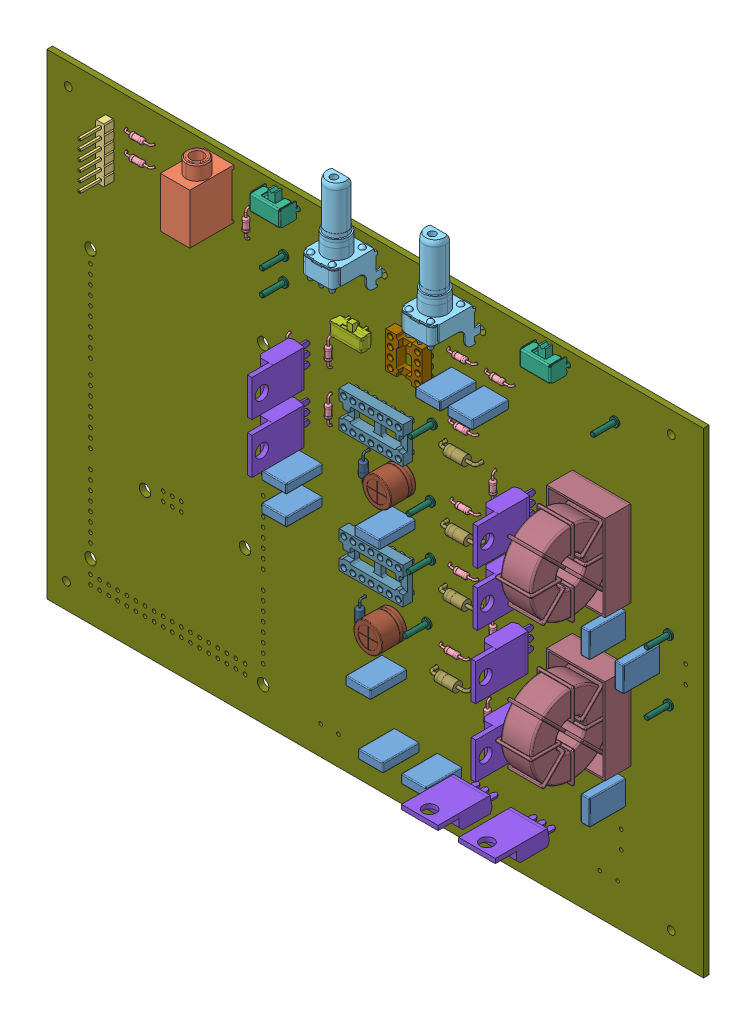
SolidWorks assembly GateDriver, configuration Default. Lengths in mm.
Overall size (183.5 153.69 35.98).
138 component instances, 16 part files, 0 mates.
Components (placement in the parent):
- GateDriver.step-1: GateDriver.step [Default] at origin size (183.5 153.69 35.98)
  - C_Rect_L7.0mm_W2.5mm_P5.00mm.step-1: C_Rect_L7.0mm_W2.5mm_P5.00mm.step [Default] at (155 -55 1.65) size (7 2.5 11.9)
    - SOLID.step-1: SOLID.step [Default] at origin size (7 2.5 11.9)
  - C_Rect_L7.0mm_W2.5mm_P5.00mm.step-2: C_Rect_L7.0mm_W2.5mm_P5.00mm.step [Default] at (151 -150.5 1.65) size (7 2.5 11.9)
    - SOLID.step-1: SOLID.step [Default] at origin size (7 2.5 11.9)
  - C_Rect_L7.0mm_W2.5mm_P5.00mm.step-3: C_Rect_L7.0mm_W2.5mm_P5.00mm.step [Default] at (164 -55 1.65) size (7 2.5 11.9)
    - SOLID.step-1: SOLID.step [Default] at origin size (7 2.5 11.9)
  - C_Rect_L7.0mm_W2.5mm_P5.00mm.step-4: C_Rect_L7.0mm_W2.5mm_P5.00mm.step [Default] at (139 -150.5 1.65) size (7 2.5 11.9)
    - SOLID.step-1: SOLID.step [Default] at origin size (7 2.5 11.9)
  - C_Rect_L7.0mm_W2.5mm_P5.00mm.step-5: C_Rect_L7.0mm_W2.5mm_P5.00mm.step [Default] at (112 -104.5 1.65) size (7 2.5 11.9)
    - SOLID.step-1: SOLID.step [Default] at origin size (7 2.5 11.9)
  - C_Rect_L7.0mm_W2.5mm_P5.00mm.step-6: C_Rect_L7.0mm_W2.5mm_P5.00mm.step [Default] at (112 -96.5 1.65) size (7 2.5 11.9)
    - SOLID.step-1: SOLID.step [Default] at origin size (7 2.5 11.9)
  - CUI_DEVICES_SJ1-3533NG.step-1: CUI_DEVICES_SJ1-3533NG.step [Default] at (90.5 -30.8 9.15) x (0 1 0) z (0 0 -1) size (18.05 8.2 15.6)
    - SOLID-0.step-1: SOLID-0.step [Default] at origin size (18.05 8.2 15.6)
  - PinHeader_1x06_P2.54mm_Vertical.step-1: PinHeader_1x06_P2.54mm_Vertical.step [Default] at (58.5 -55 1.65) x (-1 0 0) z (0 0 1) size (2.54 15.24 11.54)
    - SOLID-1.step-1: SOLID-1.step [Default] at origin size (2.54 15.24 11.54)
  - R_Axial_DIN0204_L3.6mm_D1.6mm_P7.62mm_Horizontal.step-1: R_Axial_DIN0204_L3.6mm_D1.6mm_P7.62mm_Horizontal.step [Default] at (71 -41.5 1.65) x (-1 0 0) z (0 0 1) size (8.12 1.6 4.72)
    - SOLID-2.step-1: SOLID-2.step [Default] at origin size (8.12 1.6 4.72)
  - R_Axial_DIN0204_L3.6mm_D1.6mm_P7.62mm_Horizontal.step-2: R_Axial_DIN0204_L3.6mm_D1.6mm_P7.62mm_Horizontal.step [Default] at (71 -47 1.65) x (-1 0 0) z (0 0 1) size (8.12 1.6 4.72)
    - SOLID-2.step-1: SOLID-2.step [Default] at origin size (8.12 1.6 4.72)
  - R_Axial_DIN0204_L3.6mm_D1.6mm_P7.62mm_Horizontal.step-3: R_Axial_DIN0204_L3.6mm_D1.6mm_P7.62mm_Horizontal.step [Default] at (82 -47 1.65) x (0 1 0) z (0 0 1) size (8.12 1.6 4.72)
    - SOLID-2.step-1: SOLID-2.step [Default] at origin size (8.12 1.6 4.72)
  - R_Axial_DIN0204_L3.6mm_D1.6mm_P7.62mm_Horizontal.step-4: R_Axial_DIN0204_L3.6mm_D1.6mm_P7.62mm_Horizontal.step [Default] at (97.5 -51 1.65) x (0 1 0) z (0 0 1) size (8.12 1.6 4.72)
    - SOLID-2.step-1: SOLID-2.step [Default] at origin size (8.12 1.6 4.72)
  - R_Axial_DIN0204_L3.6mm_D1.6mm_P7.62mm_Horizontal.step-5: R_Axial_DIN0204_L3.6mm_D1.6mm_P7.62mm_Horizontal.step [Default] at (153.5 -49.5 1.65) size (8.12 1.6 4.72)
    - SOLID-2.step-1: SOLID-2.step [Default] at origin size (8.12 1.6 4.72)
  - R_Axial_DIN0204_L3.6mm_D1.6mm_P7.62mm_Horizontal.step-6: R_Axial_DIN0204_L3.6mm_D1.6mm_P7.62mm_Horizontal.step [Default] at (164 -49.5 1.65) size (8.12 1.6 4.72)
    - SOLID-2.step-1: SOLID-2.step [Default] at origin size (8.12 1.6 4.72)
  - User Library-K091B0Z94 v1.step-1: User Library-K091B0Z94 v1.step [Default] at (157.5 -34 9.65) x (1 0 0) z (0 -1 0) size (9.8 16.06 30.49)
    - COMPOUND.step-1: COMPOUND.step [Default] at origin size (9.8 16.06 30.49)
  - User Library-K091B0Z94 v1.step-2: User Library-K091B0Z94 v1.step [Default] at (130 -34 9.65) x (1 0 0) z (0 -1 0) size (9.8 16.06 30.49)
    - COMPOUND.step-1: COMPOUND.step [Default] at origin size (9.8 16.06 30.49)
  - 3Pins SPDT switch SK-12D07 1P2T.step-1: 3Pins SPDT switch SK-12D07 1P2T.step [Default] at (111.35 -34.7 6.65) x (-1 0 0) z (0 0 1) size (8.6 6.94 7.5)
    - COMPOUND-3.step-1: COMPOUND-3.step [Default] at origin size (8.6 6.94 7.5)
  - SW_CuK_JS202011AQN_DPDT_Angled.step-1: SW_CuK_JS202011AQN_DPDT_Angled.step [Default] at (130.5 -59.5 1.65) x (-1 0 0) z (0 0 1) size (9 5.6 6.5)
    - SOLID-4.step-1: SOLID-4.step [Default] at origin size (9 5.6 6.5)
  - 3Pins SPDT switch SK-12D07 1P2T.step-2: 3Pins SPDT switch SK-12D07 1P2T.step [Default] at (186.85 -34.65 6.65) x (-1 0 0) z (0 0 1) size (8.6 6.94 7.5)
    - COMPOUND-3.step-1: COMPOUND-3.step [Default] at origin size (8.6 6.94 7.5)
  - TO-220-3_Vertical.step-1: TO-220-3_Vertical.step [Default] at (177.5 -151 1.65) size (10.25 4.46 28.53)
    - SOLID-5.step-1: SOLID-5.step [Default] at origin size (10.25 4.46 28.53)
  - TO-220-3_Vertical.step-2: TO-220-3_Vertical.step [Default] at (161.5 -151 1.65) size (10.25 4.46 28.53)
    - SOLID-5.step-1: SOLID-5.step [Default] at origin size (10.25 4.46 28.53)
  - DIP-8_W7.62mm_Socket.step-1: DIP-8_W7.62mm_Socket.step [Default] at (141 -51 1.65) size (10.16 10.16 7.79)
    - SOLID-6.step-1: SOLID-6.step [Default] at origin size (10.16 10.16 7.79)
  - D_DO-35_SOD27_P7.62mm_Horizontal.step-1: D_DO-35_SOD27_P7.62mm_Horizontal.step [Default] at (131 -93 1.65) x (0 1 0) z (0 0 1) size (8.12 2.33 5.01)
    - COMPOUND-7.step-1: COMPOUND-7.step [Default] at origin size (8.12 2.33 5.01)
  - C_Radial_D8.0mm_H7.0mm_P3.50mm.step-1: C_Radial_D8.0mm_H7.0mm_P3.50mm.step [Default] at (142 -87.5 1.65) x (-1 0 0) z (0 0 1) size (12.01 13.86 9)
    - SOLID-8.step-1: SOLID-8.step [Default] at origin size (12.01 13.86 9)
  - C_Rect_L7.0mm_W2.5mm_P5.00mm.step-7: C_Rect_L7.0mm_W2.5mm_P5.00mm.step [Default] at (143 -97 1.65) x (-1 0 0) z (0 0 1) size (7 2.5 11.9)
    - SOLID.step-1: SOLID.step [Default] at origin size (7 2.5 11.9)
  - C_Rect_L7.0mm_W2.5mm_P5.00mm.step-8: C_Rect_L7.0mm_W2.5mm_P5.00mm.step [Default] at (140.5 -134.5 1.65) x (-1 0 0) z (0 0 1) size (7 2.5 11.9)
    - SOLID.step-1: SOLID.step [Default] at origin size (7 2.5 11.9)
  - C_Rect_L7.0mm_W2.5mm_P5.00mm.step-9: C_Rect_L7.0mm_W2.5mm_P5.00mm.step [Default] at (201.5 -130 1.65) x (0 -1 0) z (0 0 1) size (7 2.5 11.9)
    - SOLID.step-1: SOLID.step [Default] at origin size (7 2.5 11.9)
  - D_DO-35_SOD27_P7.62mm_Horizontal.step-2: D_DO-35_SOD27_P7.62mm_Horizontal.step [Default] at (130 -129 1.65) x (0 1 0) z (0 0 1) size (8.12 2.33 5.01)
    - COMPOUND-7.step-1: COMPOUND-7.step [Default] at origin size (8.12 2.33 5.01)
  - C_Rect_L7.0mm_W2.5mm_P5.00mm.step-10: C_Rect_L7.0mm_W2.5mm_P5.00mm.step [Default] at (201.5 -89.5 1.65) x (0 -1 0) z (0 0 1) size (7 2.5 11.9)
    - SOLID.step-1: SOLID.step [Default] at origin size (7 2.5 11.9)
  - C_Radial_D8.0mm_H7.0mm_P3.50mm.step-2: C_Radial_D8.0mm_H7.0mm_P3.50mm.step [Default] at (139.5 -124 1.65) x (-1 0 0) z (0 0 1) size (12.01 13.86 9)
    - SOLID-8.step-1: SOLID-8.step [Default] at origin size (12.01 13.86 9)
  - C_Rect_L7.0mm_W2.5mm_P5.00mm.step-11: C_Rect_L7.0mm_W2.5mm_P5.00mm.step [Default] at (211 -93 1.65) x (0 -1 0) z (0 0 1) size (7 2.5 11.9)
    - SOLID.step-1: SOLID.step [Default] at origin size (7 2.5 11.9)
  - D_DO-41_SOD81_P10.16mm_Horizontal.step-1: D_DO-41_SOD81_P10.16mm_Horizontal.step [Default] at (152.5 -107.5 1.65) size (10.96 3.14 5.71)
    - SOLID-9.step-1: SOLID-9.step [Default] at origin size (10.96 3.14 5.71)
  - D_DO-41_SOD81_P10.16mm_Horizontal.step-2: D_DO-41_SOD81_P10.16mm_Horizontal.step [Default] at (153 -91.5 1.65) size (10.96 3.14 5.71)
    - SOLID-9.step-1: SOLID-9.step [Default] at origin size (10.96 3.14 5.71)
  - R_Axial_DIN0204_L3.6mm_D1.6mm_P7.62mm_Horizontal.step-7: R_Axial_DIN0204_L3.6mm_D1.6mm_P7.62mm_Horizontal.step [Default] at (161.5 -101.5 1.65) x (-1 0 0) z (0 0 1) size (8.12 1.6 4.72)
    - SOLID-2.step-1: SOLID-2.step [Default] at origin size (8.12 1.6 4.72)
  - L_CommonMode_Toroid_Vertical_L24.0mm_W16.3mm_Px10.16mm_Py20.32mm_muRATA_5200.step-1: L_CommonMode_Toroid_Vertical_L24.0mm_W16.3mm_Px10.16mm_Py20.32mm_muRATA_5200.step [Default] at (191.5 -83.5 1.65) x (0 1 0) z (0 0 1) size (24 16.3 30.48)
    - COMPOUND-10.step-1: COMPOUND-10.step [Default] at origin size (24 16.3 30.48)
  - L_CommonMode_Toroid_Vertical_L24.0mm_W16.3mm_Px10.16mm_Py20.32mm_muRATA_5200.step-2: L_CommonMode_Toroid_Vertical_L24.0mm_W16.3mm_Px10.16mm_Py20.32mm_muRATA_5200.step [Default] at (191.5 -123 1.65) x (0 1 0) z (0 0 1) size (24 16.3 30.48)
    - COMPOUND-10.step-1: COMPOUND-10.step [Default] at origin size (24 16.3 30.48)
  - TO-220-3_Vertical.step-3: TO-220-3_Vertical.step [Default] at (177 -87.5 1.65) x (0 -1 0) z (0 0 1) size (10.25 4.46 28.53)
    - SOLID-5.step-1: SOLID-5.step [Default] at origin size (10.25 4.46 28.53)
  - R_Axial_DIN0204_L3.6mm_D1.6mm_P7.62mm_Horizontal.step-8: R_Axial_DIN0204_L3.6mm_D1.6mm_P7.62mm_Horizontal.step [Default] at (161.5 -66.5 1.65) x (-1 0 0) z (0 0 1) size (8.12 1.6 4.72)
    - SOLID-2.step-1: SOLID-2.step [Default] at origin size (8.12 1.6 4.72)
  - TO-220-3_Vertical.step-4: TO-220-3_Vertical.step [Default] at (176.5 -105.5 1.65) x (0 -1 0) z (0 0 1) size (10.25 4.46 28.53)
    - SOLID-5.step-1: SOLID-5.step [Default] at origin size (10.25 4.46 28.53)
  - TO-220-3_Vertical.step-5: TO-220-3_Vertical.step [Default] at (176.5 -124.5 1.65) x (0 -1 0) z (0 0 1) size (10.25 4.46 28.53)
    - SOLID-5.step-1: SOLID-5.step [Default] at origin size (10.25 4.46 28.53)
  - TO-220-3_Vertical.step-6: TO-220-3_Vertical.step [Default] at (177 -72.5 1.65) x (0 -1 0) z (0 0 1) size (10.25 4.46 28.53)
    - SOLID-5.step-1: SOLID-5.step [Default] at origin size (10.25 4.46 28.53)
  - D_DO-41_SOD81_P10.16mm_Horizontal.step-3: D_DO-41_SOD81_P10.16mm_Horizontal.step [Default] at (152.5 -72.5 1.65) size (10.96 3.14 5.71)
    - SOLID-9.step-1: SOLID-9.step [Default] at origin size (10.96 3.14 5.71)
  - D_DO-41_SOD81_P10.16mm_Horizontal.step-4: D_DO-41_SOD81_P10.16mm_Horizontal.step [Default] at (150 -128.5 1.65) size (10.96 3.14 5.71)
    - SOLID-9.step-1: SOLID-9.step [Default] at origin size (10.96 3.14 5.71)
  - R_Axial_DIN0204_L3.6mm_D1.6mm_P7.62mm_Horizontal.step-9: R_Axial_DIN0204_L3.6mm_D1.6mm_P7.62mm_Horizontal.step [Default] at (162 -85.5 1.65) x (-1 0 0) z (0 0 1) size (8.12 1.6 4.72)
    - SOLID-2.step-1: SOLID-2.step [Default] at origin size (8.12 1.6 4.72)
  - R_Axial_DIN0204_L3.6mm_D1.6mm_P7.62mm_Horizontal.step-10: R_Axial_DIN0204_L3.6mm_D1.6mm_P7.62mm_Horizontal.step [Default] at (159 -122 1.65) x (-1 0 0) z (0 0 1) size (8.12 1.6 4.72)
    - SOLID-2.step-1: SOLID-2.step [Default] at origin size (8.12 1.6 4.72)
  - R_Axial_DIN0204_L3.6mm_D1.6mm_P7.62mm_Horizontal.step-11: R_Axial_DIN0204_L3.6mm_D1.6mm_P7.62mm_Horizontal.step [Default] at (166.5 -72.5 1.65) x (0 -1 0) z (0 0 1) size (8.12 1.6 4.72)
    - SOLID-2.step-1: SOLID-2.step [Default] at origin size (8.12 1.6 4.72)
  - R_Axial_DIN0204_L3.6mm_D1.6mm_P7.62mm_Horizontal.step-12: R_Axial_DIN0204_L3.6mm_D1.6mm_P7.62mm_Horizontal.step [Default] at (166.5 -107.5 1.65) x (0 -1 0) z (0 0 1) size (8.12 1.6 4.72)
    - SOLID-2.step-1: SOLID-2.step [Default] at origin size (8.12 1.6 4.72)
  - R_Axial_DIN0204_L3.6mm_D1.6mm_P7.62mm_Horizontal.step-13: R_Axial_DIN0204_L3.6mm_D1.6mm_P7.62mm_Horizontal.step [Default] at (167.5 -91.5 1.65) x (0 -1 0) z (0 0 1) size (8.12 1.6 4.72)
    - SOLID-2.step-1: SOLID-2.step [Default] at origin size (8.12 1.6 4.72)
  - R_Axial_DIN0204_L3.6mm_D1.6mm_P7.62mm_Horizontal.step-14: R_Axial_DIN0204_L3.6mm_D1.6mm_P7.62mm_Horizontal.step [Default] at (165 -128.5 1.65) x (0 -1 0) z (0 0 1) size (8.12 1.6 4.72)
    - SOLID-2.step-1: SOLID-2.step [Default] at origin size (8.12 1.6 4.72)
  - DIP-14_W7.62mm_Socket.step-1: DIP-14_W7.62mm_Socket.step [Default] at (128 -113.5 1.65) x (0 1 0) z (0 0 1) size (10.16 17.78 7.79)
    - SOLID-11.step-1: SOLID-11.step [Default] at origin size (10.16 17.78 7.79)
  - DIP-14_W7.62mm_Socket.step-2: DIP-14_W7.62mm_Socket.step [Default] at (128 -79.5 1.65) x (0 1 0) z (0 0 1) size (10.16 17.78 7.79)
    - SOLID-11.step-1: SOLID-11.step [Default] at origin size (10.16 17.78 7.79)
  - TO-220-3_Vertical.step-7: TO-220-3_Vertical.step [Default] at (114 -68 1.65) x (0 -1 0) z (0 0 1) size (10.25 4.46 28.53)
    - SOLID-5.step-1: SOLID-5.step [Default] at origin size (10.25 4.46 28.53)
  - TO-220-3_Vertical.step-8: TO-220-3_Vertical.step [Default] at (114 -82 1.65) x (0 -1 0) z (0 0 1) size (10.25 4.46 28.53)
    - SOLID-5.step-1: SOLID-5.step [Default] at origin size (10.25 4.46 28.53)
  - R_Axial_DIN0204_L3.6mm_D1.6mm_P7.62mm_Horizontal.step-15: R_Axial_DIN0204_L3.6mm_D1.6mm_P7.62mm_Horizontal.step [Default] at (120.5 -63 1.65) x (0 -1 0) z (0 0 1) size (8.12 1.6 4.72)
    - SOLID-2.step-1: SOLID-2.step [Default] at origin size (8.12 1.6 4.72)
  - R_Axial_DIN0204_L3.6mm_D1.6mm_P7.62mm_Horizontal.step-16: R_Axial_DIN0204_L3.6mm_D1.6mm_P7.62mm_Horizontal.step [Default] at (108.5 -82 1.65) x (0 -1 0) z (0 0 1) size (8.12 1.6 4.72)
    - SOLID-2.step-1: SOLID-2.step [Default] at origin size (8.12 1.6 4.72)
  - R_Axial_DIN0204_L3.6mm_D1.6mm_P7.62mm_Horizontal.step-17: R_Axial_DIN0204_L3.6mm_D1.6mm_P7.62mm_Horizontal.step [Default] at (120.5 -77 1.65) x (0 -1 0) z (0 0 1) size (8.12 1.6 4.72)
    - SOLID-2.step-1: SOLID-2.step [Default] at origin size (8.12 1.6 4.72)
  - R_Axial_DIN0204_L3.6mm_D1.6mm_P7.62mm_Horizontal.step-18: R_Axial_DIN0204_L3.6mm_D1.6mm_P7.62mm_Horizontal.step [Default] at (109 -68 1.65) x (0 -1 0) z (0 0 1) size (8.12 1.6 4.72)
    - SOLID-2.step-1: SOLID-2.step [Default] at origin size (8.12 1.6 4.72)
  - Pin_D1.3mm_L11.0mm.step-1: Pin_D1.3mm_L11.0mm.step [Default] at (200 -44 1.65) size (2.5 2.89 11)
    - SOLID-12.step-1: SOLID-12.step [Default] at origin size (2.5 2.89 11)
  - Pin_D1.3mm_L11.0mm.step-2: Pin_D1.3mm_L11.0mm.step [Default] at (107.5 -56.5 1.65) size (2.5 2.89 11)
    - SOLID-12.step-1: SOLID-12.step [Default] at origin size (2.5 2.89 11)
  - Pin_D1.3mm_L11.0mm.step-3: Pin_D1.3mm_L11.0mm.step [Default] at (107.5 -50 1.65) size (2.5 2.89 11)
    - SOLID-12.step-1: SOLID-12.step [Default] at origin size (2.5 2.89 11)
  - Pin_D1.3mm_L11.0mm.step-4: Pin_D1.3mm_L11.0mm.step [Default] at (149 -70 1.65) size (2.5 2.89 11)
    - SOLID-12.step-1: SOLID-12.step [Default] at origin size (2.5 2.89 11)
  - Pin_D1.3mm_L11.0mm.step-5: Pin_D1.3mm_L11.0mm.step [Default] at (148.5 -89 1.65) size (2.5 2.89 11)
    - SOLID-12.step-1: SOLID-12.step [Default] at origin size (2.5 2.89 11)
  - Pin_D1.3mm_L11.0mm.step-6: Pin_D1.3mm_L11.0mm.step [Default] at (148.5 -103 1.65) size (2.5 2.89 11)
    - SOLID-12.step-1: SOLID-12.step [Default] at origin size (2.5 2.89 11)
  - Pin_D1.3mm_L11.0mm.step-7: Pin_D1.3mm_L11.0mm.step [Default] at (147.5 -119 1.65) size (2.5 2.89 11)
    - SOLID-12.step-1: SOLID-12.step [Default] at origin size (2.5 2.89 11)
  - Pin_D1.3mm_L11.0mm.step-8: Pin_D1.3mm_L11.0mm.step [Default] at (186 -91.5 1.65) size (2.5 2.89 11)
    - SOLID-12.step-1: SOLID-12.step [Default] at origin size (2.5 2.89 11)
  - Pin_D1.3mm_L11.0mm.step-9: Pin_D1.3mm_L11.0mm.step [Default] at (183.5 -123 1.65) size (2.5 2.89 11)
    - SOLID-12.step-1: SOLID-12.step [Default] at origin size (2.5 2.89 11)
  - Pin_D1.3mm_L11.0mm.step-10: Pin_D1.3mm_L11.0mm.step [Default] at (215 -88 1.65) size (2.5 2.89 11)
    - SOLID-12.step-1: SOLID-12.step [Default] at origin size (2.5 2.89 11)
  - Pin_D1.3mm_L11.0mm.step-11: Pin_D1.3mm_L11.0mm.step [Default] at (215 -105 1.65) size (2.5 2.89 11)
    - SOLID-12.step-1: SOLID-12.step [Default] at origin size (2.5 2.89 11)
  - _autosave-GateDriver PCB.step-1: _autosave-GateDriver PCB.step [Default] at origin size (183.5 133 1.6)
